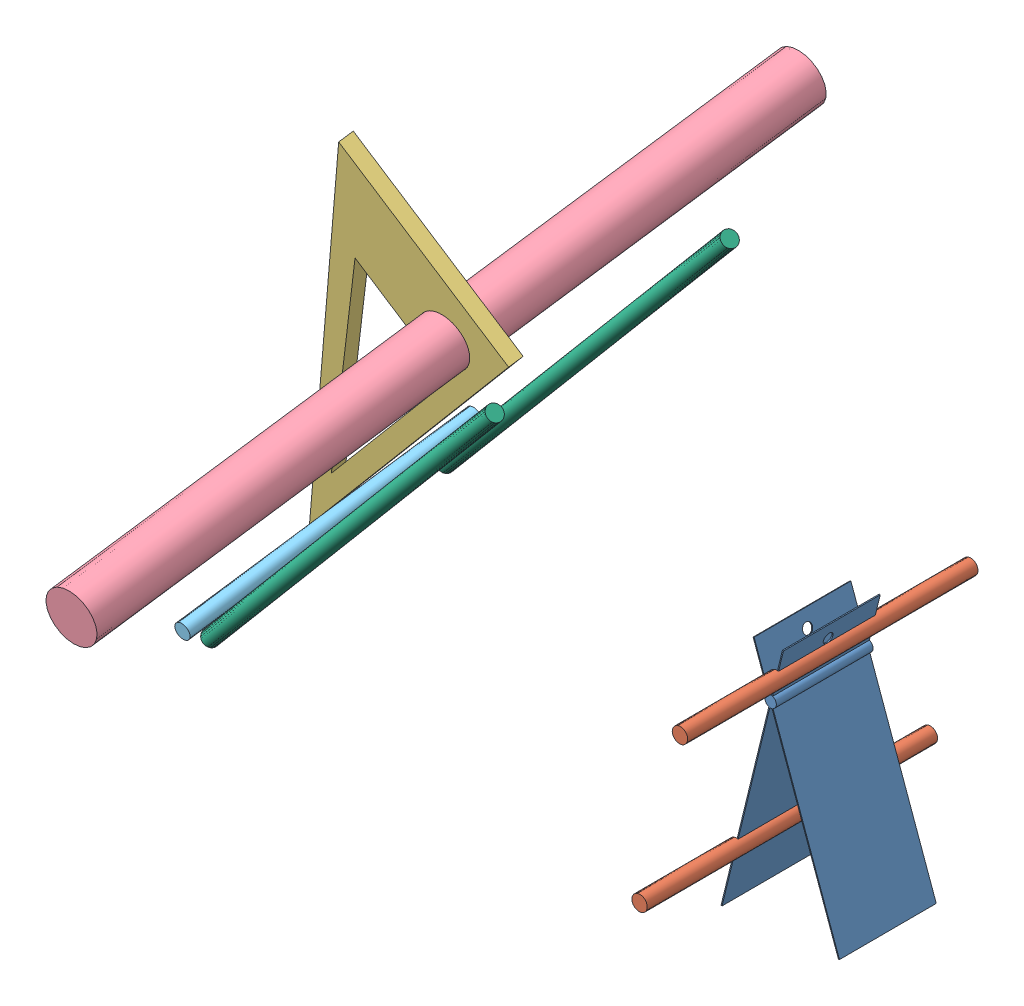
SolidWorks assembly 发射装置, configuration 默认. Lengths in mm.
Overall size (154.36 100.01 150.31).
8 component instances, 6 part files, 15 mates.
Components (placement in the parent):
- 夹子-1: 夹子 [默认] at (-0.6687 15.4816 -0.2854) x (-0.214062 -0.976296 0.031992) z (0.029034 0.026377 0.99923) size (50 27.6 20)
- 撑夹子杆-1: 撑夹子杆 [默认] at (-7.2308 -12.7928 -19.3637) x (0.976388 -0.214826 -0.022699) z (-0.214062 -0.976296 0.031992) size (3 60 3)
- 撑夹子杆-2: 撑夹子杆 [默认] at (1.5578 20.9275 39.537) x (0.976388 -0.214826 -0.022699) z (0.214062 0.976296 -0.031992) size (3 60 3)
- 三角-1: 三角 [默认] at (-67.8077 44.0329 14.5055) x (-0.650171 -0.75557 -0.079953) z (0.018013 -0.120531 0.992546) size (70 40 3)
- 粗杆-2: 粗杆 [默认] at (-69.0745 52.5093 -55.2963) x (0.018013 -0.120531 0.992546) z (-0.041152 -0.991955 -0.119712) size (150 10 10)
- 细杆60-2: 细杆60 [默认] at (-96.8079 -1.2377 -17.5607) x (-0.621922 0.775938 0.105514) z (0.018013 -0.120531 0.992546) size (3 3 60)
- 细杆100-1: 细杆100 [默认] at (-97.2522 -13.9119 34.8793) x (0.07674 -0.169997 0.982452) z (0.650171 0.75557 0.079953) size (3 3 100)
- 细杆100-2: 细杆100 [默认] at (-98.2817 -8.2497 -13.2618) x (0.754723 -0.630121 -0.182593) z (0.650171 0.75557 0.079953) size (3 3 100)
Mates (geometry in assembly coordinates):
- 重合1: coincident anti-aligned: plane of 夹子-1 through (-0.2249 14.9181 19.732) normal (0.976388 -0.214826 -0.022699); plane of 撑夹子杆-1 through (3.6606 33.6994 9.1156) normal (-0.976388 0.214826 0.022699)
- 重合2: coincident anti-aligned: plane of 夹子-1 through (-0.088 16.0091 19.6992) normal (0.029034 0.026377 0.99923); plane of 撑夹子杆-1 through (-35.1046 42.5562 20.0159) normal (-0.029034 -0.026377 -0.99923)
- 重合3: coincident anti-aligned: plane of 夹子-1 through (2.1503 25.7506 19.377) normal (0.976388 -0.214826 -0.022699); plane of 撑夹子杆-2 through (-9.3336 -25.5647 11.0576) normal (-0.976388 0.214826 0.022699)
- 重合4: coincident anti-aligned: plane of 夹子-1 through (-0.088 16.0091 19.6992) normal (0.029034 0.026377 0.99923); plane of 撑夹子杆-2 through (-48.0988 -16.7078 21.9579) normal (-0.029034 -0.026377 -0.99923)
- 锁定3: lock: unknown of ?; unknown of ?
- 锁定4: lock: unknown of ?; unknown of ?
- 同心1: concentric aligned: cylinder of 三角-1 through (-67.7536 43.6713 17.4831) axis (-0.018013 0.120531 -0.992546) radius 5; cylinder of 粗杆-2 through (-66.3725 34.4297 93.5857) axis (-0.018013 0.120531 -0.992546) radius 5
- 相切1: tangent anti-aligned: plane of 三角-1 through (-54.8473 45.5861 17.4814) normal (0.759574 -0.643884 -0.091976); cylinder of 细杆60-2 through (-95.7271 -8.4696 41.9921) axis (-0.018013 0.120531 -0.992546) radius 1.5
- 平行1: parallel anti-aligned: line of 三角-1 through (-100.4133 -6.9422 8.9071) axis (0.650171 0.75557 0.079953); line of 细杆100-1 through (-32.2351 61.6451 42.8746) axis (-0.650171 -0.75557 -0.079953)
- 平行2: parallel anti-aligned: line of 三角-1 through (-100.3593 -7.3038 11.8847) axis (0.650171 0.75557 0.079953); line of 细杆100-2 through (-33.2646 67.3073 -5.2665) axis (-0.650171 -0.75557 -0.079953)
- 相切2: tangent anti-aligned: cylinder of 细杆60-2 through (-95.7271 -8.4696 41.9921) axis (-0.018013 0.120531 -0.992546) radius 1.5; cylinder of 细杆100-2 through (-33.2646 67.3073 -5.2665) axis (-0.650171 -0.75557 -0.079953) radius 1.5
- 相切3: tangent anti-aligned: cylinder of 细杆60-2 through (-95.7271 -8.4696 41.9921) axis (-0.018013 0.120531 -0.992546) radius 1.5; cylinder of 细杆100-1 through (-32.2351 61.6451 42.8746) axis (-0.650171 -0.75557 -0.079953) radius 1.5
- 平行3: parallel aligned: line of 三角-1 through (-100.3593 -7.3038 11.8847) axis (-0.018013 0.120531 -0.992546); line of 细杆60-2 through (-95.7271 -8.4696 41.9921) axis (-0.018013 0.120531 -0.992546)
- 锁定5: lock: unknown of 细杆60-2; unknown of 细杆100-2
- 锁定6: lock: unknown of 细杆60-2; unknown of 细杆100-1
